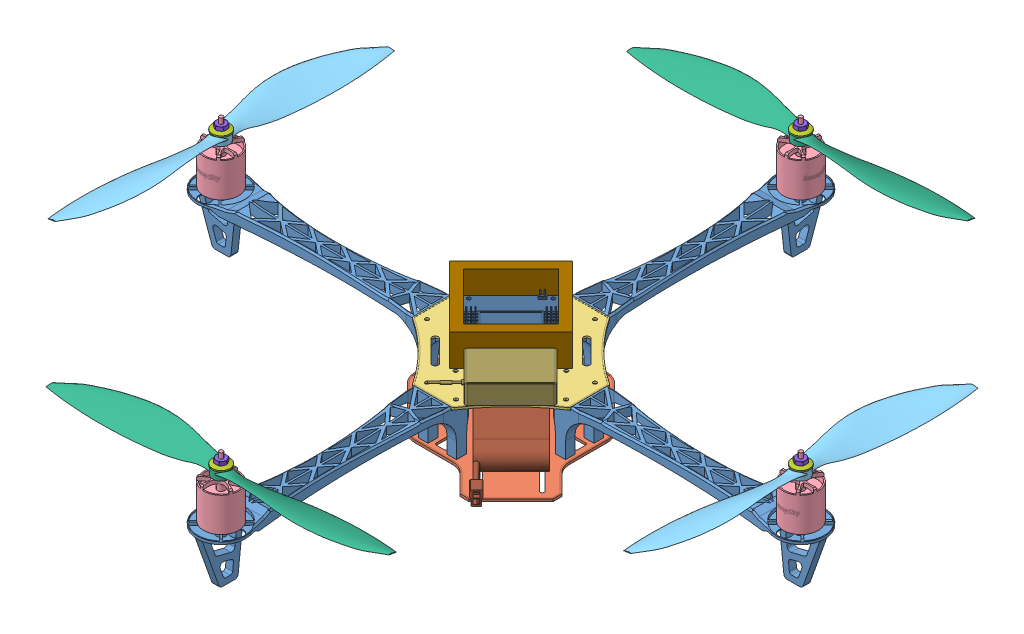
SolidWorks assembly Quadcopter Assembly New, configuration Default. Lengths in mm.
Overall size (552.74 90.52 553.62).
26 component instances, 12 part files, 65 mates.
Components (placement in the parent):
- leggggs-1: leggggs [Default] at (-161.4605 -19.0123 29.8165) size (215.9 47.13 45.4)
- leggggs-2: leggggs [Default] at (297.8315 -19.0123 29.8165) x (-1 0 0) z (0 0 -1) size (215.9 47.13 45.4)
- leggggs-3: leggggs [Default] at (68.1855 -19.0123 -199.8295) x (0 0 1) z (-1 0 0) size (215.9 47.13 45.4)
- leggggs-4: leggggs [Default] at (68.1855 -19.0123 259.4625) x (0 0 -1) z (1 0 0) size (215.9 47.13 45.4)
- PCB Board-3: PCB Board [Default] at (68.1855 -2.0139 29.8165) x (0.707107 0 0.707107) z (0 1 0) size (180 116.27 1.95)
- Top PCB Board-8: Top PCB Board [Default] at (68.1859 36.1236 29.8165) x (1 0 0) z (0 -1 0) size (124.5 124.5 1.7)
- motor-1: motor [Default] at (68.1855 35.3367 259.4625) x (0 0 1) z (-1 0 0) size (27.5 47.5 27.5)
- motor-2: motor [Default] at (68.1855 35.3367 -199.8295) x (0 0 -1) z (1 0 0) size (27.5 47.5 27.5)
- motor-3: motor [Default] at (297.8315 35.3367 29.8165) size (27.5 47.5 27.5)
- motor-4: motor [Default] at (-161.4605 35.3367 29.8165) size (27.5 47.5 27.5)
- 10x4.7-1: 10x4.7 [Default] at (303.2654 67.3367 32.9649) x (-0.992231 0 0.124411) z (-0.124411 0 -0.992231) size (60.03 10.54 246.43)
- 10x4.7-2: 10x4.7 [Default] at (-166.9785 67.3367 26.8179) x (0.988456 0 -0.151509) z (0.151509 0 0.988456) size (60.03 10.54 246.43)
- 10x4.7 clockwise-1: 10x4.7 clockwise [Default] at (63.7011 67.3367 -195.4329) x (0.144901 0 -0.989446) z (0.989446 0 0.144901) size (60.03 10.54 246.43)
- 10x4.7 clockwise-2: 10x4.7 clockwise [Default] at (63.7302 67.3367 263.8886) x (0.138381 0 -0.990379) z (0.990379 0 0.138381) size (60.03 10.54 246.43)
- washer-1: washer [Default] at (297.8315 73.5367 29.8165) x (1 0 0) z (0 1 0) size (14 14 2)
- washer-3: washer [Default] at (68.1855 73.5367 -199.8295) x (-0.269757 0 0.962928) z (0 1 0) size (14 14 2)
- washer-4: washer [Default] at (68.1855 73.5367 259.4625) x (1 0 0) z (0 1 0) size (14 14 2)
- washer-5: washer [Default] at (-161.4605 73.5367 29.8165) x (0.734464 0 0.678647) z (0 1 0) size (14 14 2)
- Nut-1: Nut [Default] at (-161.4605 77.0367 25.3165) x (0.866025 0 0.5) z (0 -1 0) size (9 7.79 3)
- Nut-2: Nut [Default] at (65.9355 77.0367 -195.9324) x (-0.5 0 -0.866025) z (0 -1 0) size (9 7.79 3)
- Nut-3: Nut [Default] at (65.9355 77.0367 263.3596) x (-0.5 0 -0.866025) z (0 -1 0) size (9 7.79 3)
- Nut-4: Nut [Default] at (297.8315 77.0367 25.3165) x (0.866025 0 0.5) z (0 -1 0) size (9 7.79 3)
- foam box-1: foam box [Default] at (55.846 49.3736 66.2643) x (0 1 0) z (-0.707107 0 0.707107) size (25 69 69)
- kk2board-1: kk2board [Default] at (55.846 41.8736 54.9506) x (0.707107 0 -0.707107) z (0 1 0) size (53 53 8)
- battery-1: battery [Default] at (110.6714 -1.1389 72.1834) x (0.707107 0 -0.707107) z (0.707107 0 0.707107) size (44.75 20 172.87)
- Receiver-1: Receiver [Default] at (87.0967 44.3736 85.9253) x (0.707107 0 -0.707107) z (0 1 0) size (72.4 35 15)
Mates (geometry in assembly coordinates):
- Parallel6: parallel anti-aligned: plane of leggggs-1 through (9.927 -1.1389 331.3733) normal (0 -1 0); plane of PCB Board-3 through (53.4453 -1.1389 -46.442) normal (0 1 0)
- Coincident43: coincident anti-aligned: circle of leggggs-3; circle of PCB Board-3
- Coincident44: coincident anti-aligned: circle of leggggs-3; circle of PCB Board-3
- Concentric29: concentric anti-aligned: circle of leggggs-1; circle of PCB Board-3
- Coincident46: coincident anti-aligned: circle of leggggs-1; circle of PCB Board-3
- Concentric30: concentric anti-aligned: circle of leggggs-4; circle of PCB Board-3
- Coincident48: coincident anti-aligned: circle of leggggs-4; circle of PCB Board-3
- Concentric31: concentric anti-aligned: cylinder of leggggs-2 through (122.444 6.3611 19.3165) axis (0 -1 0) radius 1.5; circle of PCB Board-3
- Coincident50: coincident anti-aligned: circle of leggggs-2; circle of PCB Board-3
- Parallel7: parallel anti-aligned: plane of PCB Board-3 through (53.4453 -1.1389 -46.442) normal (0 1 0); plane of Top PCB Board-8 through (218.0594 35.3736 179.69) normal (0 -1 0)
- Concentric33: concentric anti-aligned: circle of leggggs-4; circle of Top PCB Board-8
- Coincident56: coincident anti-aligned: plane of leggggs-3 through (-233.3713 35.3736 -2.9795) normal (0 1 0); plane of Top PCB Board-8 through (218.0594 35.3736 179.69) normal (0 -1 0)
- Coincident57: coincident anti-aligned: cylinder of leggggs-1 through (13.0809 14.7334 41.3165) axis (0 1 0) radius 1.5; circle of Top PCB Board-8
- Concentric34: concentric anti-aligned: circle of leggggs-4; circle of motor-1
- Concentric35: concentric anti-aligned: cylinder of leggggs-4 through (74.903 -20.5433 266.18) axis (0 1 0) radius 1.5; cylinder of motor-1 through (74.903 42.3367 266.18) axis (0 -1 0) radius 1.5
- Coincident59: coincident anti-aligned: plane of leggggs-4 through (369.7423 35.3367 240.4125) normal (0 1 0); plane of motor-1 through (68.1855 35.3367 259.4625) normal (0 -1 0)
- Concentric36: concentric anti-aligned: cylinder of leggggs-1 through (-168.178 -20.5433 36.534) axis (0 1 0) radius 1.5; cylinder of motor-4 through (-168.178 42.3367 36.534) axis (0 -1 0) radius 1.5
- Coincident60: coincident anti-aligned: circle of leggggs-1; cylinder of motor-4 through (-154.743 42.3367 23.099) axis (0 -1 0) radius 1.5
- Coincident61: coincident anti-aligned: plane of leggggs-1 through (-142.4105 35.3367 331.3733) normal (0 1 0); plane of motor-4 through (-161.4605 35.3367 29.8165) normal (0 -1 0)
- Concentric37: concentric anti-aligned: cylinder of leggggs-2 through (304.549 -20.5433 23.099) axis (0 1 0) radius 1.5; cylinder of motor-3 through (304.549 42.3367 23.099) axis (0 -1 0) radius 1.5
- Coincident62: coincident anti-aligned: cylinder of leggggs-2 through (291.114 -20.5433 36.534) axis (0 1 0) radius 1.5; circle of motor-3
- Coincident63: coincident anti-aligned: plane of leggggs-2 through (278.7815 35.3367 -271.7403) normal (0 1 0); plane of motor-3 through (297.8315 35.3367 29.8165) normal (0 -1 0)
- Coincident64: coincident anti-aligned: circle of leggggs-3; cylinder of motor-2 through (61.468 42.3367 -206.547) axis (0 -1 0) radius 1.5
- Concentric38: concentric anti-aligned: cylinder of leggggs-3 through (74.903 -20.5433 -193.112) axis (0 1 0) radius 1.5; cylinder of motor-2 through (74.903 42.3367 -193.112) axis (0 -1 0) radius 1.5
- Coincident66: coincident anti-aligned: plane of leggggs-3 through (-233.3713 35.3367 -180.7795) normal (0 1 0); plane of motor-2 through (68.1855 35.3367 -199.8295) normal (0 -1 0)
- Concentric39: concentric aligned: cylinder of motor-3 through (297.8315 82.8367 29.8165) axis (0 -1 0) radius 1.5; cylinder of 10x4.7-1 through (297.8315 71.3367 29.8165) axis (0 -1 0) radius 4
- Coincident67: coincident anti-aligned: plane of motor-3 through (297.8315 66.8367 29.8165) normal (0 1 0); plane of 10x4.7-1 through (297.8315 66.8367 29.8165) normal (0 -1 0)
- Concentric40: concentric aligned: cylinder of motor-4 through (-161.4605 82.8367 29.8165) axis (0 -1 0) radius 1.5; cylinder of 10x4.7-2 through (-161.4605 71.3367 29.8165) axis (0 -1 0) radius 4
- Coincident68: coincident anti-aligned: plane of motor-4 through (-161.4605 66.8367 29.8165) normal (0 1 0); plane of 10x4.7-2 through (-161.4605 66.8367 29.8165) normal (0 -1 0)
- Concentric41: concentric aligned: cylinder of motor-1 through (68.1855 82.8367 259.4625) axis (0 -1 0) radius 1.5; cylinder of 10x4.7 clockwise-2 through (68.1855 71.3367 259.4625) axis (0 -1 0) radius 4
- Coincident69: coincident anti-aligned: plane of motor-1 through (68.1855 66.8367 259.4625) normal (0 1 0); plane of 10x4.7 clockwise-2 through (68.1855 66.8367 259.4625) normal (0 -1 0)
- Concentric42: concentric anti-aligned: cylinder of motor-2 through (68.1855 82.8367 -199.8295) axis (0 -1 0) radius 1.5; circle of 10x4.7 clockwise-1
- Coincident70: coincident anti-aligned: plane of motor-2 through (68.1855 66.8367 -199.8295) normal (0 1 0); plane of 10x4.7 clockwise-1 through (68.1855 66.8367 -199.8295) normal (0 -1 0)
- Coincident71: coincident anti-aligned: plane of 10x4.7 clockwise-2 through (68.1855 73.5367 259.4625) normal (0 1 0); plane of washer-4 through (68.1855 73.5367 259.4625) normal (0 -1 0)
- Concentric43: concentric aligned: cylinder of motor-1 through (68.1855 82.8367 259.4625) axis (0 -1 0) radius 1.5; cylinder of washer-4 through (68.1855 75.5367 259.4625) axis (0 -1 0) radius 1.5
- Concentric44: concentric aligned: cylinder of motor-4 through (-161.4605 82.8367 29.8165) axis (0 -1 0) radius 1.5; circle of washer-5
- Coincident72: coincident anti-aligned: plane of 10x4.7-2 through (-161.4605 73.5367 29.8165) normal (0 1 0); plane of washer-5 through (-161.4605 73.5367 29.8165) normal (0 -1 0)
- Coincident73: coincident anti-aligned: plane of 10x4.7-1 through (297.8315 73.5367 29.8165) normal (0 1 0); plane of washer-1 through (297.8315 73.5367 29.8165) normal (0 -1 0)
- Concentric45: concentric aligned: cylinder of motor-3 through (297.8315 82.8367 29.8165) axis (0 -1 0) radius 1.5; cylinder of washer-1 through (297.8315 75.5367 29.8165) axis (0 -1 0) radius 1.5
- Concentric46: concentric aligned: cylinder of motor-2 through (68.1855 82.8367 -199.8295) axis (0 -1 0) radius 1.5; cylinder of washer-3 through (68.1855 75.5367 -199.8295) axis (0 -1 0) radius 1.5
- Coincident74: coincident anti-aligned: plane of 10x4.7 clockwise-1 through (68.1855 73.5367 -199.8295) normal (0 1 0); plane of washer-3 through (68.1855 73.5367 -199.8295) normal (0 -1 0)
- Concentric47: concentric anti-aligned: cylinder of motor-4 through (-161.4605 82.8367 29.8165) axis (0 -1 0) radius 1.5; cylinder of Nut-1 through (-161.4605 75.5367 29.8165) axis (0 1 0) radius 1.5
- Coincident75: coincident anti-aligned: plane of washer-5 through (-161.4605 75.5367 29.8165) normal (0 1 0); plane of Nut-1 through (-161.4605 75.5367 25.3165) normal (0 -1 0)
- Concentric48: concentric anti-aligned: cylinder of motor-1 through (68.1855 82.8367 259.4625) axis (0 -1 0) radius 1.5; cylinder of Nut-3 through (68.1855 75.5367 259.4625) axis (0 1 0) radius 1.5
- Coincident76: coincident anti-aligned: plane of washer-4 through (68.1855 75.5367 259.4625) normal (0 1 0); plane of Nut-3 through (65.9355 75.5367 263.3596) normal (0 -1 0)
- Concentric49: concentric anti-aligned: cylinder of motor-3 through (297.8315 82.8367 29.8165) axis (0 -1 0) radius 1.5; cylinder of Nut-4 through (297.8315 75.5367 29.8165) axis (0 1 0) radius 1.5
- Coincident79: coincident anti-aligned: plane of washer-1 through (297.8315 75.5367 29.8165) normal (0 1 0); plane of Nut-4 through (297.8315 75.5367 25.3165) normal (0 -1 0)
- Coincident80: coincident aligned: cylinder of motor-2 through (68.1855 82.8367 -199.8295) axis (0 -1 0) radius 1.5; circle of Nut-2
- Coincident81: coincident anti-aligned: plane of washer-3 through (68.1855 75.5367 -199.8295) normal (0 1 0); plane of Nut-2 through (65.9355 75.5367 -195.9324) normal (0 -1 0)
- Parallel8: parallel aligned: plane of leggggs-4 through (56.3605 36.8677 62.6125) normal (0 0 -1); plane of Nut-3 through (70.4355 75.5367 255.5654) normal (0 0 -1)
- Parallel9: parallel anti-aligned: plane of leggggs-4 through (56.3605 36.8677 62.6125) normal (0 0 -1); plane of Nut-2 through (65.9355 75.5367 -195.9324) normal (0 0 1)
- Parallel10: parallel anti-aligned: plane of leggggs-2 through (100.9815 36.8677 41.6415) normal (-1 0 0); plane of Nut-4 through (301.7286 75.5367 32.0665) normal (1 0 0)
- Parallel11: parallel anti-aligned: plane of leggggs-2 through (100.9815 36.8677 41.6415) normal (-1 0 0); plane of Nut-1 through (-157.5634 75.5367 32.0665) normal (1 0 0)
- Tangent2: tangent anti-aligned: cylinder of Top PCB Board-8 through (-81.6876 35.3736 -120.057) axis (0 1 0) radius 160; plane of foam box-1 through (7.0556 61.8736 17.474) normal (-0.707107 0 -0.707107)
- Coincident90: coincident anti-aligned: plane of Top PCB Board-8 through (218.0594 36.8736 179.69) normal (0 1 0); plane of foam box-1 through (55.846 36.8736 66.2643) normal (0 -1 0)
- Parallel15: parallel aligned: plane of PCB Board-3 through (115.2081 -1.1389 110.0731) normal (0.707107 0 0.707107); plane of foam box-1 through (55.846 61.8736 66.2643) normal (0.707107 0 0.707107)
- Distance4: distance = 5.455 mm aligned: plane of foam box-1 through (55.846 61.8736 66.2643) normal (-0.707107 0 0.707107); plane of Top PCB Board-8 through (48.4201 36.8736 66.553) normal (-0.707107 0 0.707107)
- Coincident96: coincident anti-aligned: plane of foam box-1 through (55.846 41.8736 66.2643) normal (0 1 0); plane of kk2board-1 through (55.846 41.8736 54.9506) normal (0 -1 0)
- Coincident100: coincident anti-aligned: plane of foam box-1 through (93.3226 41.8736 17.474) normal (-0.707107 0 0.707107); plane of kk2board-1 through (93.3226 43.8736 17.474) normal (0.707107 0 -0.707107)
- Coincident101: coincident anti-aligned: plane of foam box-1 through (55.846 41.8736 -20.0027) normal (0.707107 0 0.707107); plane of kk2board-1 through (18.3693 43.8736 17.474) normal (-0.707107 0 -0.707107)
- Coincident102: coincident anti-aligned: plane of PCB Board-3 through (53.4453 -1.1389 -46.442) normal (0 1 0); plane of battery-1 through (125.8742 -1.1389 56.9806) normal (0 -1 0)
- Parallel16: parallel aligned: plane of foam box-1 through (104.6363 61.8736 17.474) normal (0.707107 0 -0.707107); plane of battery-1 through (125.8742 8.8611 56.9806) normal (0.707107 0 -0.707107)
- Coincident106: coincident anti-aligned: plane of PCB Board-3 through (115.2081 -1.1389 110.0731) normal (0.707107 0 0.707107); plane of battery-1 through (120.3927 11.6405 104.8886) normal (-0.707107 0 -0.707107)
- Coincident107: coincident anti-aligned: plane of Top PCB Board-8 through (218.0594 36.8736 179.69) normal (0 1 0); plane of Receiver-1 through (87.0967 36.8736 85.9253) normal (0 -1 0)
- Distance5: distance = 1 mm anti-aligned: plane of foam box-1 through (55.846 61.8736 66.2643) normal (0.707107 0 0.707107); plane of Receiver-1 through (62.348 51.8736 61.1766) normal (-0.707107 0 -0.707107)
